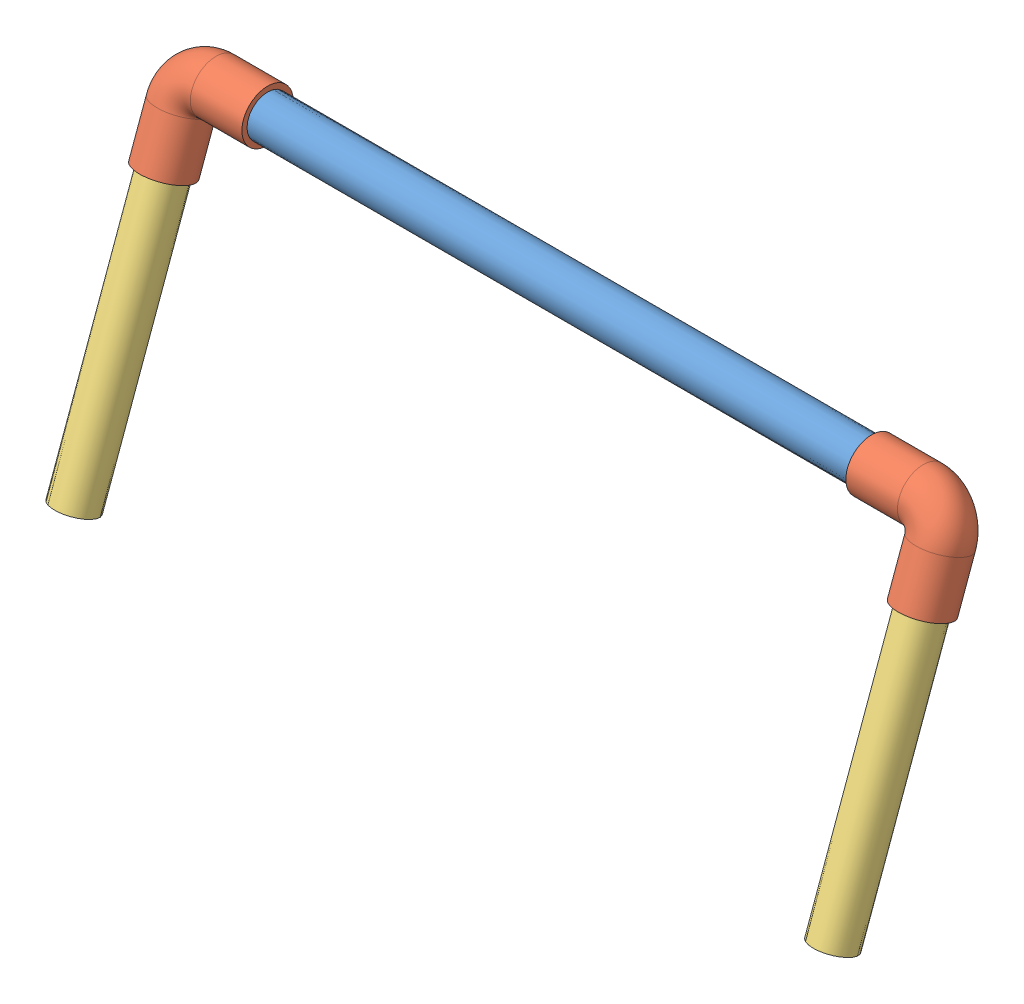
SolidWorks assembly Assem1, configuration Default. Lengths in mm.
Overall size (524.74 233.95 113.02).
5 component instances, 3 part files, 13 mates.
Components (placement in the parent):
- 18_inch_pvc_white-1: 18_inch_pvc_white [Default] at (-42.5541 284.8611 306.218) x (0 0 -1) z (1 0 0) size (26.67 26.67 457.2)
- ELBOW 90 Degree 19.0500 mm-1: ELBOW 90 Degree 19.0500 mm [Default] at (-59.1911 237.8713 323.305) x (1 0 0) z (0 0.34174 0.939794) size (66.64 66.64 33.27)
- ELBOW 90 Degree 19.0500 mm-2: ELBOW 90 Degree 19.0500 mm [Default] at (381.2829 284.8611 306.218) x (0 -0.939794 0.34174) z (0 0.34174 0.939794) size (66.64 66.64 33.27)
- 8_inch_pvc_white-1: 8_inch_pvc_white [Default] at (-59.1911 78.2595 381.3451) x (-0.912136 -0.140075 -0.385211) z (0.409889 -0.311713 -0.85722) size (26.67 203.2 26.67)
- 8_inch_pvc_white-2: 8_inch_pvc_white [Default] at (431.2829 269.2257 311.9035) x (-0.971434 0.081098 0.223022) z (0.237309 0.331978 0.912949) size (26.67 203.2 26.67)
Mates (geometry in assembly coordinates):
- Concentric1: concentric aligned: circle of 18_inch_pvc_white-1; circle of ELBOW 90 Degree 19.0500 mm-1
- Concentric2: concentric aligned: circle of 18_inch_pvc_white-1; circle of ELBOW 90 Degree 19.0500 mm-2
- Parallel1: parallel aligned: cylinder of ELBOW 90 Degree 19.0500 mm-1 through (-59.1911 269.2257 311.9035) axis (0 -0.939794 0.34174) radius 13.1572; cylinder of 8_inch_pvc_white-1 through (-59.1911 269.2257 311.9035) axis (0 -0.939794 0.34174) radius 13.335
- Parallel2: parallel anti-aligned: cylinder of ELBOW 90 Degree 19.0500 mm-2 through (431.2829 269.2257 311.9035) axis (0 -0.939794 0.34174) radius 13.1572; cylinder of 8_inch_pvc_white-2 through (431.2829 78.2595 381.3451) axis (0 0.939794 -0.34174) radius 13.335
- Concentric7: concentric aligned: circle of ELBOW 90 Degree 19.0500 mm-1; circle of 8_inch_pvc_white-1
- Concentric8: concentric aligned: circle of ELBOW 90 Degree 19.0500 mm-2; circle of 8_inch_pvc_white-2
- Concentric10: concentric anti-aligned: cylinder of 18_inch_pvc_white-1 through (414.6459 284.8611 306.218) axis (-1 0 0) radius 13.335; cylinder of ELBOW 90 Degree 19.0500 mm-1 through (-42.5541 284.8611 306.218) axis (1 0 0) radius 13.1572
- Concentric13: concentric aligned: circle of ELBOW 90 Degree 19.0500 mm-1; circle of 8_inch_pvc_white-1
- Coincident1: coincident aligned: plane of ELBOW 90 Degree 19.0500 mm-1; plane of 8_inch_pvc_white-1 through (-59.1911 269.2257 311.9035) normal (0 0.939794 -0.34174)
- Coincident2: coincident anti-aligned: plane of 18_inch_pvc_white-1 through (-42.5541 284.8611 306.218) normal (-1 0 0); circle of ELBOW 90 Degree 19.0500 mm-1
- Coincident3: coincident aligned: plane of 18_inch_pvc_white-1 through (414.6459 284.8611 306.218) normal (1 0 0); circle of ELBOW 90 Degree 19.0500 mm-2
- Coincident4: coincident anti-aligned: circle of ELBOW 90 Degree 19.0500 mm-2; plane of 8_inch_pvc_white-2 through (431.2829 269.2257 311.9035) normal (0 0.939794 -0.34174)
- Parallel6: parallel anti-aligned: cylinder of 8_inch_pvc_white-1 through (-59.1911 269.2257 311.9035) axis (0 -0.939794 0.34174) radius 13.335; cylinder of 8_inch_pvc_white-2 through (431.2829 78.2595 381.3451) axis (0 0.939794 -0.34174) radius 13.335
